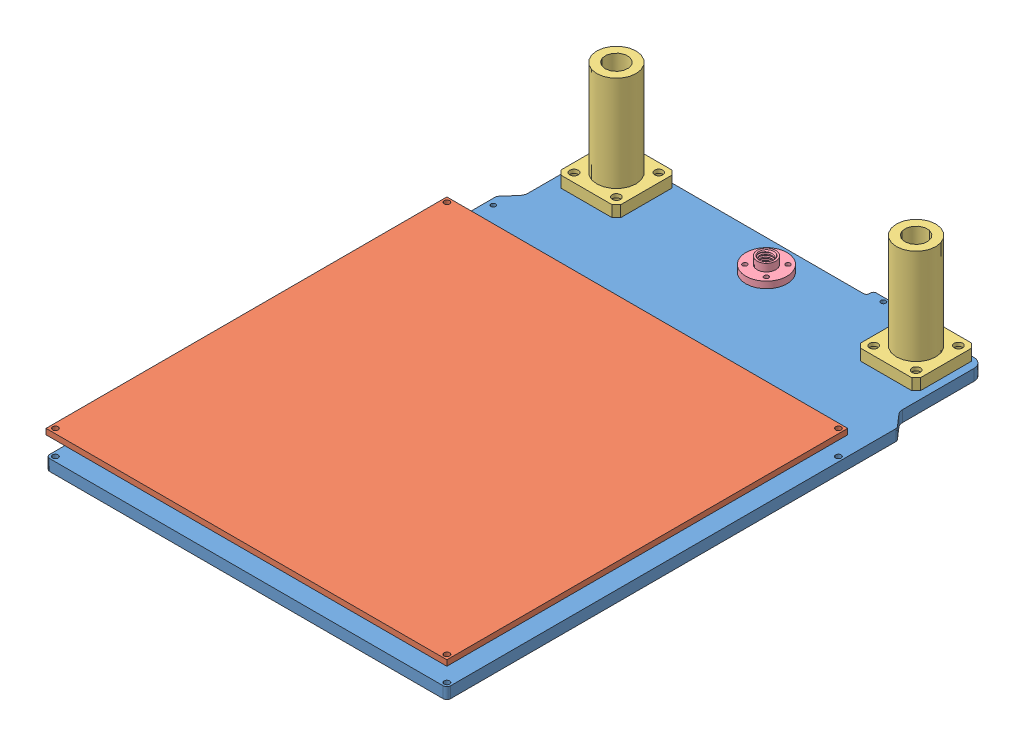
SolidWorks assembly HeatBedAssembly, configuration По умолчанию. Lengths in mm.
Overall size (214 63 297.2).
6 component instances, 4 part files, 18 mates.
Components (placement in the parent):
- 1153-B2P-B-1: 1153-B2P-B [По умолчанию] at (156.1029 153.1976 202.4625) size (214 6 297.2)
- HEATBED MK3-1: HEATBED MK3 [По умолчанию] at (152.3949 172.1976 247.7704) size (214 3 214)
- HEATBED MK3-2: HEATBED MK3 [По умолчанию] at (152.3949 175.1976 247.7704) size (214 3 214) (suppressed, hidden)
- 1170-B2P-B-1: 1170-B2P-B [По умолчанию] at (72.3949 159.1976 77.2704) size (32 57 32)
- 1170-B2P-B-2: 1170-B2P-B [По умолчанию] at (232.3949 159.1976 77.2704) size (32 57 32)
- 1187-B2P-A-1: 1187-B2P-A [По умолчанию] at (152.3949 160.9476 77.1704) size (22 11.99 22)
Mates (geometry in assembly coordinates):
- Концентричный3: concentric anti-aligned: circle of 1153-B2P-B-1; circle of HEATBED MK3-1
- Параллельность1: parallel aligned: plane of 1153-B2P-B-1 through (45.3949 159.1976 115.0006) normal (-1 0 0); plane of HEATBED MK3-1 through (45.3949 172.1976 354.7704) normal (-1 0 0)
- Концентричный5: concentric anti-aligned: circle of 1153-B2P-B-1; circle of HEATBED MK3-1
- Расстояние1: distance = 13 mm aligned: plane of 1153-B2P-B-1 through (247.3659 159.1976 66.2704) normal (0 1 0); plane of HEATBED MK3-1 through (152.3949 172.1976 247.7704) normal (0 1 0)
- Совпадение12: coincident anti-aligned: plane of HEATBED MK3-1 through (152.3949 172.1976 247.7704) normal (0 1 0); plane of HEATBED MK3-2 through (152.3949 172.1976 247.7704) normal (0 -1 0)
- Совпадение13: coincident aligned: plane of HEATBED MK3-1 through (259.3949 172.1976 354.7704) normal (0 0 1); plane of HEATBED MK3-2 through (259.3949 175.1976 354.7704) normal (0 0 1)
- Совпадение14: coincident aligned: plane of HEATBED MK3-1 through (259.3949 172.1976 140.7704) normal (1 0 0); plane of HEATBED MK3-2 through (259.3949 175.1976 140.7704) normal (1 0 0)
- Концентричный6: concentric anti-aligned: circle of 1153-B2P-B-1; circle of 1170-B2P-B-2
- Концентричный7: concentric anti-aligned: circle of 1153-B2P-B-1; circle of 1170-B2P-B-2
- Концентричный8: concentric anti-aligned: circle of 1153-B2P-B-1; circle of 1170-B2P-B-2
- Совпадение15: coincident anti-aligned: plane of 1153-B2P-B-1 through (247.3659 159.1976 66.2704) normal (0 1 0); plane of 1170-B2P-B-2 through (232.3949 159.1976 77.2704) normal (0 -1 0)
- Концентричный9: concentric anti-aligned: circle of 1153-B2P-B-1; circle of 1170-B2P-B-1
- Концентричный10: concentric anti-aligned: circle of 1153-B2P-B-1; circle of 1170-B2P-B-1
- Концентричный11: concentric anti-aligned: circle of 1153-B2P-B-1; circle of 1170-B2P-B-1
- Совпадение16: coincident anti-aligned: plane of 1153-B2P-B-1 through (247.3659 159.1976 66.2704) normal (0 1 0); plane of 1170-B2P-B-1 through (72.3949 159.1976 77.2704) normal (0 -1 0)
- Концентричный12: concentric anti-aligned: circle of 1153-B2P-B-1; circle of 1187-B2P-A-1
- Концентричный13: concentric anti-aligned: circle of 1153-B2P-B-1; circle of 1187-B2P-A-1
- Совпадение18: coincident anti-aligned: plane of 1153-B2P-B-1 through (247.3659 159.1976 66.2704) normal (0 1 0); plane of 1187-B2P-A-1 through (152.3949 159.1976 82.1704) normal (0 -1 0)
